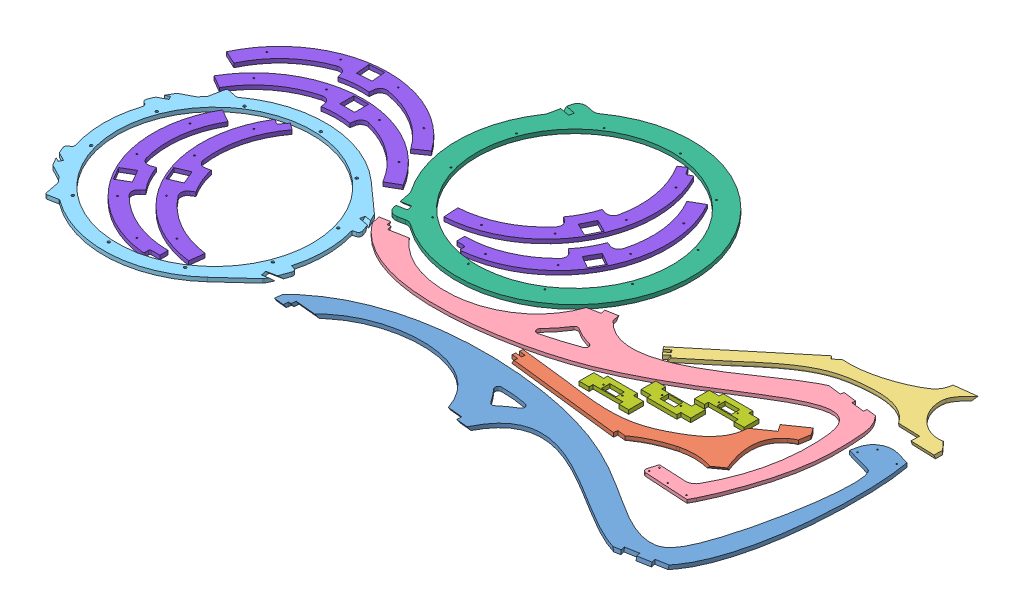
SolidWorks assembly Cutting Layout, configuration Default. Lengths in mm.
Overall size (2523 852.5 1210.8).
15 component instances, 8 part files, 15 mates.
Components (placement in the parent):
- Right Side Plus Offset-2: Right Side Plus Offset [Default] at (-791.5678 108.0853 1219.3767) x (0.987506 -0.156822 -0.015465) z (0.137122 0.806779 0.574722) size (1393.16 574.9 379.93)
- mirror Support 2-1: mirror Support 2 [Default] at (-343.6944 533.5214 722.885) x (0.560735 0.825471 0.064603) z (-0.820046 0.564444 -0.094479) size (365.24 345.16 526.43)
- mirror Support-1: mirror Support [Default] at (99.4872 0 341.709) x (0.770192 0 -0.637812) z (0 -1 0) size (686.18 345.16 12)
- Copy of Lest Side Plus Offset^Cutting Layout-1: Copy of Lest Side Plus Offset^Cutting Layout [Default] at (-867.2905 77.5777 463.0035) x (0.989514 -0.133516 -0.05509) z (-0.05509 -0.701466 0.710571) size (1295.77 378.22 374.28) (virtual)
- Circular Base layer 2-1: Circular Base layer 2 [Default] at (-1538.9474 0 848.6813) x (1 0 0) z (0 -1 0) size (674.73 670 12)
- Circular Base-1: Circular Base [Default] at (-938.0629 -10 362.2731) size (711 12 711)
- Base - Uprights-1: Base - Uprights [Default] at (-284.0253 220.248 617.9856) x (1 0 0) z (0 -1 0) size (150 56.45 12)
- Base - Uprights-2: Base - Uprights [Default] at (-179.0894 -232.248 746.9188) x (1 0 0) z (0 1 0) size (150 56.45 12)
- Base - Uprights-3: Base - Uprights [Default] at (-399.5502 -232.248 875.1797) x (1 0 0) z (0 1 0) size (150 56.45 12)
- Base - Cable carrier ring-1: Base - Cable carrier ring [NoSlot Section 1] at (-1346.154 -518.3606 752.4849) x (-0.602828 0 0.797871) z (0 -1 0) size (330 493.11 12)
- Base - Cable carrier ring-2: Base - Cable carrier ring [NoSlot Section 2] at (-1444.9098 -518.3606 798.6071) x (1 0 0) z (0 -1 0) size (330 493.11 12)
- Base - Cable carrier ring-3: Base - Cable carrier ring [NoSlot Section 3] at (-1577.601 -518.3606 614.6913) x (0.996207 0 -0.087017) z (0 -1 0) size (571.58 187.5 12)
- Base - Cable carrier ring-4: Base - Cable carrier ring [Section 1] at (-1036.2301 -518.3606 313.6964) x (1 0 0) z (0 -1 0) size (327.5 493.11 12)
- Base - Cable carrier ring-5: Base - Cable carrier ring [Section 2] at (-1136.1958 -518.3606 249.5534) x (-0.551625 0 -0.834092) z (0 -1 0) size (327.5 493.11 12)
- Base - Cable carrier ring-6: Base - Cable carrier ring [Section 3] at (-1546.8934 -518.3606 722.2769) x (1 0 0) z (0 -1 0) size (571.58 187.5 12)
Mates (geometry in assembly coordinates):
- Coincident1: coincident aligned: plane of Right Side Plus Offset-2 through (-791.5678 0 1219.3767) normal (0 1 0); plane of assembly through (0 0 0) normal (0 1 0)
- Coincident3: coincident aligned: plane of mirror Support 2-1 through (-266.1858 0 823.8244) normal (0 1 0); plane of assembly through (0 0 0) normal (0 1 0)
- Coincident4: coincident aligned: plane of mirror Support-1 through (-107.4262 0 394.3805) normal (0 1 0); plane of assembly through (0 0 0) normal (0 1 0)
- Coincident5: coincident aligned: plane of Right Side Plus Offset-2 through (-791.5678 0 1219.3767) normal (0 1 0); plane of Copy of Lest Side Plus Offset^Cutting Layout-1 through (-867.2905 0 463.0035) normal (0 1 0)
- Coincident6: coincident aligned: plane of Right Side Plus Offset-2 through (-791.5678 0 1219.3767) normal (0 1 0); plane of assembly through (0 0 0) normal (0 1 0)
- Coincident7: coincident aligned: plane of Copy of Lest Side Plus Offset^Cutting Layout-1 through (-867.2905 0 463.0035) normal (0 1 0); plane of assembly through (0 0 0) normal (0 1 0)
- Coincident8: coincident aligned: plane of assembly through (0 0 0) normal (0 1 0); plane of Base - Uprights-1 through (-366.2828 0 732.9004) normal (0 1 0)
- Coincident9: coincident aligned: plane of assembly through (0 0 0) normal (0 1 0); plane of Base - Uprights-2 through (-261.3468 0 632.004) normal (0 1 0)
- Coincident10: coincident aligned: plane of assembly through (0 0 0) normal (0 1 0); plane of Base - Uprights-3 through (-481.8077 0 760.2648) normal (0 1 0)
- Coincident11: coincident aligned: plane of Base - Cable carrier ring-1 through (-1346.154 0 752.4849) normal (0 1 0); plane of assembly through (0 0 0) normal (0 1 0)
- Coincident12: coincident aligned: plane of Base - Cable carrier ring-1 through (-1346.154 0 752.4849) normal (0 1 0); plane of Base - Cable carrier ring-2 through (-1444.9098 0 798.6071) normal (0 1 0)
- Coincident13: coincident aligned: plane of Base - Cable carrier ring-2 through (-1444.9098 0 798.6071) normal (0 1 0); plane of Base - Cable carrier ring-3 through (-1577.601 0 614.6913) normal (0 1 0)
- Coincident14: coincident aligned: plane of Base - Cable carrier ring-3 through (-1577.601 0 614.6913) normal (0 1 0); plane of Base - Cable carrier ring-4 through (-1036.2301 0 313.6964) normal (0 1 0)
- Coincident15: coincident aligned: plane of Base - Cable carrier ring-3 through (-1577.601 0 614.6913) normal (0 1 0); plane of Base - Cable carrier ring-5 through (-1136.1958 0 249.5534) normal (0 1 0)
- Coincident16: coincident aligned: plane of Base - Cable carrier ring-5 through (-1136.1958 0 249.5534) normal (0 1 0); plane of Base - Cable carrier ring-6 through (-1546.8934 0 722.2769) normal (0 1 0)
